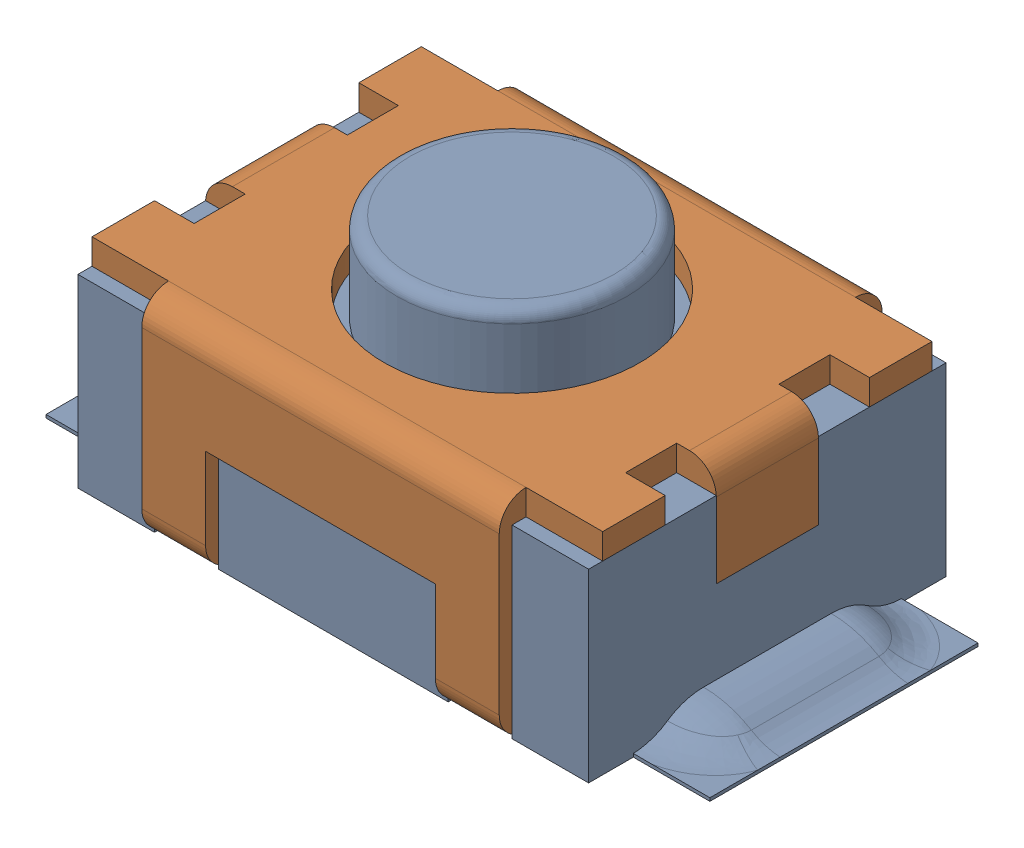
SolidWorks assembly reset button, configuration Predeterminado. Lengths in mm.
Overall size (5.21 2.15 3).
2 component instances, 2 part files, 0 mates.
Components (placement in the parent):
- reset core-1: reset core [Predeterminado] at origin size (5.21 2.15 2.8)
- reset shell-1: reset shell [Predeterminado] at (0 1.65 0) x (0 0 1) z (-1 0 0) size (3 1.65 4)
